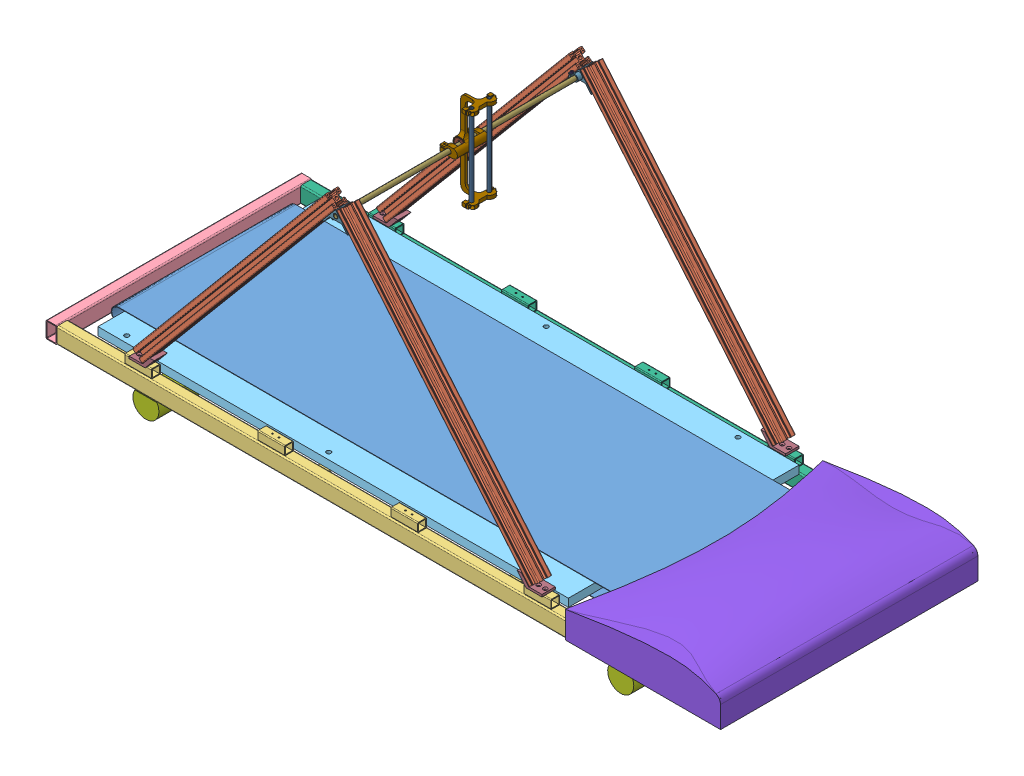
SolidWorks assembly treadmill, configuration Default. Lengths in mm.
37 component instances, 17 part files, 89 mates.
Components (placement in the parent):
- running_area-1: running_area [Default] at origin size (1202 32 400)
- Bosch Profile - 30x30-1: Bosch Profile - 30x30 [Predeterminado] at (-18.609 533.7218 -274.5) x (0 0 -1) z (-0.642788 -0.766044 0) size (30 30 675)
- Bosch Profile - 30x30-2: Bosch Profile - 30x30 [Predeterminado] at (6.609 533.7218 -274.5) x (0 0 1) z (0.642788 -0.766044 0) size (30 30 675)
- Bosch Profile - 30x30-3: Bosch Profile - 30x30 [Predeterminado] at (-18.609 533.7218 274.5) x (0 0 -1) z (-0.642788 -0.766044 0) size (30 30 675)
- Bosch Profile - 30x30-4: Bosch Profile - 30x30 [Predeterminado] at (6.609 533.7218 274.5) x (0 0 1) z (0.642788 -0.766044 0) size (30 30 675)
- Structure - right side-1: Structure - right side [Default] at (-636 -55 274.5) x (0 0 -1) z (1 0 0) size (54 57 1470)
- Structure - front-1: Structure - front [Default] at (-648.5 -55 0) size (25 37 574)
- Structure - front-2: Structure - front [Default] at (846.5 -55 0) size (25 37 574)
- Structure - table-1: Structure - table [Default] at (-571 -18 0) x (0 0 -1) z (1 0 0) size (520 18 1060)
- MirrorStructure - right side-3: MirrorStructure - right side [Default] at (-636 -55 -274.5) x (0 0 1) z (-1 0 0) size (54 57 1470)
- Structure - legs-1: Structure - legs [Default] at (-436 -55 0) size (58.89 45 574)
- Structure - legs-3: Structure - legs [Default] at (634 -55 0) size (58.89 45 574)
- Cover-1: Cover [Default] at (862 -55 0) x (0 0 -1) z (1 0 0) size (598.07 112.89 350.23)
- Interface - Robot holder-1: Interface - Robot holder [Default] at (25.0619 512.5003 0) x (0 0 -1) z (1 0 0) size (70 190 68.16)
- Interface - Jumping rods-1: Interface - Jumping rods [Default] at (30.7648 512.5003 -20) x (0 1 0) z (0 0 1) size (190 8 8)
- Interface - Jumping rods-2: Interface - Jumping rods [Default] at (30.7648 512.5003 20) x (0 1 0) z (-0.99626 0 0.086407) size (190 8 8)
- bearing_S 6000-2RS_618-9991-1: bearing_S 6000-2RS_618-9991 [Predeterminado] at (-6 512.5003 -9.8) size (26 26 8)
- bearing_S 6000-2RS_618-9991-2: bearing_S 6000-2RS_618-9991 [Predeterminado] at (-6 512.5003 1.8) size (26 26 8)
- Interface - Structure rod-1: Interface - Structure rod [Default] at (-6 512.5003 0) x (0 1 0) z (-1 0 0) size (10 579 10)
- Printed Parts - Profile - Treadmill-1: Printed Parts - Profile - Treadmill [Default] at (429 7 -274.5) x (0 0 -1) z (1 0 0) size (30 24.15 56.07)
- Printed Parts - Profile - Treadmill-2: Printed Parts - Profile - Treadmill [Default] at (-441 7 -274.5) x (0 0 1) z (-1 0 0) size (30 24.15 56.07)
- Printed Parts - Profile - Treadmill-3: Printed Parts - Profile - Treadmill [Default] at (-441 7 274.5) x (0 0 1) z (-1 0 0) size (30 24.15 56.07)
- Printed Parts - Profile - Treadmill-4: Printed Parts - Profile - Treadmill [Default] at (429 7 274.5) x (0 0 -1) z (1 0 0) size (30 24.15 56.07)
- Printed Parts - Profile - Robot-1: Printed Parts - Profile - Robot [Default] at (-6 512.5003 -274.5) x (0 0 -1) z (1 0 0) size (40 36.53 58.07)
- Printed Parts - Profile - Robot-2: Printed Parts - Profile - Robot [Default] at (-6 512.5003 274.5) x (0 0 1) z (-1 0 0) size (40 36.53 58.07)
- DIN 912 M6 x 10 --- 10N-6: DIN 912 M6 x 10 --- 10N [DIN 912 M6 x 10 --- 10N] at (413.3693 14.3327 -274.5) x (0.766044 0.642788 0) z (-0.079258 0.094456 0.992369) size (16 10 10)
- DIN 912 M6 x 10 --- 10N-10: DIN 912 M6 x 10 --- 10N [DIN 912 M6 x 10 --- 10N] at (-425.3693 14.3327 -274.5) x (-0.766044 0.642788 0) z (0.478639 0.570419 -0.667478) size (16 10 10)
- DIN 912 M6 x 10 --- 10N-11: DIN 912 M6 x 10 --- 10N [DIN 912 M6 x 10 --- 10N] at (413.3693 14.3327 274.5) x (0.766044 0.642788 0) z (0.079258 -0.094456 -0.992369) size (16 10 10)
- DIN 912 M6 x 10 --- 10N-12: DIN 912 M6 x 10 --- 10N [DIN 912 M6 x 10 --- 10N] at (-425.3693 14.3327 274.5) x (-0.766044 0.642788 0) z (0.478639 0.570419 -0.667478) size (16 10 10)
- DIN 912 M6 x 10 --- 10N-13: DIN 912 M6 x 10 --- 10N [DIN 912 M6 x 10 --- 10N] at (9.7148 492.6831 -274.5) x (0.766044 0.642788 0) z (0.596176 -0.710494 -0.373861) size (16 10 10)
- DIN 912 M6 x 10 --- 10N-14: DIN 912 M6 x 10 --- 10N [DIN 912 M6 x 10 --- 10N] at (-21.7148 492.6831 -274.5) x (-0.766044 0.642788 0) z (0.474764 0.565802 -0.674141) size (16 10 10)
- DIN 912 M6 x 10 --- 10N-15: DIN 912 M6 x 10 --- 10N [DIN 912 M6 x 10 --- 10N] at (-21.7148 492.6831 274.5) x (-0.766044 0.642788 0) z (0.474764 0.565802 -0.674141) size (16 10 10)
- DIN 912 M6 x 10 --- 10N-16: DIN 912 M6 x 10 --- 10N [DIN 912 M6 x 10 --- 10N] at (9.7148 492.6831 274.5) x (0.766044 0.642788 0) z (0.596176 -0.710494 -0.373861) size (16 10 10)
- klee M3x5-1: klee M3x5 [Default] at (4.5366 505.2503 253.5) x (1 0 0) z (0 -1 0) size (4.8 4.8 6.21)
- klee M3x5-2: klee M3x5 [Default] at (-16.5366 505.2503 -253.5) x (1 0 0) z (0 -1 0) size (4.8 4.8 6.21)
- DIN 912 M3 x 6 --- 6N-1: DIN 912 M3 x 6 --- 6N [DIN 912 M3 x 6 --- 6N] at (-16.5366 518.7503 -253.5) x (0 -1 0) z (0.377809 0 0.925884) size (9 5.5 5.5)
- DIN 912 M3 x 6 --- 6N-2: DIN 912 M3 x 6 --- 6N [DIN 912 M3 x 6 --- 6N] at (4.5366 518.7503 253.5) x (0 -1 0) z (0.377809 0 0.925884) size (9 5.5 5.5)
Mates (geometry in assembly coordinates):
- Coincident1: coincident: plane of running_area-1 through (0 0 0) normal (0 0 1); plane of assembly through (0 0 0) normal (0 0 1)
- Coincident2: coincident: plane of running_area-1 through (0 0 0) normal (0 1 0); plane of assembly through (0 0 0) normal (0 1 0)
- Coincident3: coincident aligned: plane of running_area-1 through (0 0 0) normal (1 0 0); plane of assembly through (0 0 0) normal (1 0 0)
- Coincident11: coincident aligned: plane of Bosch Profile - 30x30-1 through (-456.5507 20.0486 -259.5) normal (0 0 1); plane of Bosch Profile - 30x30-2 through (444.5507 20.0486 -259.5) normal (0 0 1)
- Coincident16: coincident aligned: plane of Bosch Profile - 30x30-3 through (-456.5507 20.0486 289.5) normal (0 0 1); plane of Bosch Profile - 30x30-4 through (444.5507 20.0486 289.5) normal (0 0 1)
- Width1: width anti-aligned: plane of Structure - table-1 through (-571 0 -260) normal (0 0 -1); plane of Structure - table-1 through (-571 0 260) normal (0 0 1); plane of running_area-1 through (-585 -15 200) normal (0 0 1); plane of running_area-1 through (-585 -15 -200) normal (0 0 -1)
- Concentric1: concentric anti-aligned: cylinder of Structure - right side-1 through (-521 -25 245) axis (0 -1 0) radius 4; cylinder of Structure - table-1 through (-521 -18 245) axis (0 1 0) radius 5
- Parallel1: parallel anti-aligned: plane of Structure - right side-1 through (834 -21 262) normal (0 0 -1); plane of Structure - table-1 through (-571 0 260) normal (0 0 1)
- Coincident18: coincident anti-aligned: plane of Structure - right side-1 through (834 -21 284) normal (1 0 0); plane of Structure - front-2 through (834 -21 287) normal (-1 0 0)
- Coincident19: coincident aligned: plane of Structure - right side-1 through (834 -21 287) normal (0 0 1); plane of Structure - front-2 through (837 -21 287) normal (0 0 1)
- Coincident20: coincident aligned: plane of Structure - right side-1 through (834 -21 287) normal (0 0 1); plane of Structure - front-1 through (-658 -21 287) normal (0 0 1)
- Coincident21: coincident aligned: plane of Structure - right side-1 through (834 -18 284) normal (0 1 0); plane of Structure - front-1 through (-658 -18 287) normal (0 1 0)
- Coincident22: coincident anti-aligned: plane of Structure - right side-1 through (-636 -21 284) normal (-1 0 0); plane of Structure - front-1 through (-636 -21 287) normal (1 0 0)
- Coincident23: coincident aligned: plane of Structure - right side-1 through (834 -18 284) normal (0 1 0); plane of Structure - front-2 through (837 -18 287) normal (0 1 0)
- Coincident25: coincident anti-aligned: plane of running_area-1 through (-585 0 200) normal (0 -1 0); plane of Structure - table-1 through (-571 0 0) normal (0 1 0)
- Distance1: distance = 35 mm anti-aligned: cylinder of running_area-1 through (-585 -15 200) axis (0 0 -1) radius 16; plane of Structure - front-1 through (-636 -21 287) normal (1 0 0)
- Coincident27: coincident aligned: plane of MirrorStructure - right side-3 through (834 -21 -287) normal (0 0 -1); plane of Structure - legs-1 through (-436 -70.5556 -287) normal (0 0 -1)
- Coincident29: coincident aligned: plane of Structure - legs-1 through (-436 -70.5556 -287) normal (0 0 -1); plane of Structure - legs-3 through (634 -70.5556 -287) normal (0 0 -1)
- Coincident33: coincident anti-aligned: plane of MirrorStructure - right side-3 through (834 -55 -284) normal (0 -1 0); plane of Structure - legs-1 through (-461 -55 287) normal (0 1 0)
- Coincident34: coincident anti-aligned: plane of Structure - right side-1 through (834 -18 284) normal (0 1 0); plane of Structure - table-1 through (-571 -18 0) normal (0 -1 0)
- Distance2: distance = 200 mm: point of Structure - legs-1; plane of Structure - front-1 through (-661 -21 287) normal (-1 0 0)
- Distance3: distance = 200 mm: point of Structure - legs-3; plane of Structure - front-2 through (859 -21 287) normal (1 0 0)
- Width2: width anti-aligned: plane of Cover-1 through (691.5068 28.631 287) normal (0 0 -1); plane of Cover-1 through (691.5068 28.631 -287) normal (0 0 1); plane of Structure - right side-1 through (834 -21 287) normal (0 0 1); plane of MirrorStructure - right side-3 through (834 -21 -287) normal (0 0 -1)
- Coincident39: coincident anti-aligned: plane of Structure - front-2 through (859 -21 287) normal (1 0 0); plane of Cover-1 through (859 -55 290) normal (-1 0 0)
- Coincident41: coincident aligned: plane of MirrorStructure - right side-3 through (834 -55 -284) normal (0 -1 0); plane of Cover-1 through (512 -55 290) normal (0 -1 0)
- Concentric2: concentric anti-aligned: cylinder of Interface - Jumping rods-1 through (47.6845 587.3362 -20) axis (0 -1 0) radius 4; cylinder of Interface - Robot holder-1 through (47.6845 579.3362 -20) axis (0 1 0) radius 4.35
- Coincident42: coincident aligned: plane of Interface - Robot holder-1 through (53.3874 587.3362 -2.5) normal (0 1 0); plane of Interface - Jumping rods-1 through (47.6845 587.3362 -20) normal (0 1 0)
- Concentric3: concentric anti-aligned: cylinder of Interface - Robot holder-1 through (47.6845 579.3362 20) axis (0 1 0) radius 4.35; cylinder of Interface - Jumping rods-2 through (47.6845 587.3362 20) axis (0 -1 0) radius 4
- Coincident43: coincident aligned: plane of Interface - Robot holder-1 through (53.3874 587.3362 -2.5) normal (0 1 0); plane of Interface - Jumping rods-2 through (47.6845 587.3362 20) normal (0 1 0)
- Width3: width anti-aligned: plane of Interface - Robot holder-1 through (41.9816 492.3362 -2.5) normal (0 0 -1); plane of Interface - Robot holder-1 through (41.9816 492.3362 2.5) normal (0 0 1); plane of Bosch Profile - 30x30-4 through (444.5507 20.0486 289.5) normal (0 0 1); plane of Bosch Profile - 30x30-2 through (444.5507 20.0486 -289.5) normal (0 0 -1)
- Concentric4: concentric aligned: cylinder of Interface - Robot holder-1 through (10.9197 492.3362 -1.8) axis (0 0 -1) radius 13.6; cylinder of bearing_S 6000-2RS_618-9991-1 through (10.9197 492.3362 -1.8) axis (0 0 -1) radius 5
- Coincident44: coincident anti-aligned: plane of Interface - Robot holder-1 through (10.9197 492.3362 -1.8) normal (0 0 -1); plane of bearing_S 6000-2RS_618-9991-1 through (10.9197 492.3362 -1.8) normal (0 0 1)
- Concentric6: concentric anti-aligned: cylinder of Interface - Robot holder-1 through (10.9197 492.3362 -10) axis (0 0 1) radius 15; cylinder of bearing_S 6000-2RS_618-9991-2 through (10.9197 492.3362 9.8) axis (0 0 -1) radius 13
- Coincident45: coincident anti-aligned: plane of Interface - Robot holder-1 through (10.9197 492.3362 1.8) normal (0 0 1); plane of bearing_S 6000-2RS_618-9991-2 through (10.9197 492.3362 1.8) normal (0 0 -1)
- Concentric7: concentric anti-aligned: cylinder of bearing_S 6000-2RS_618-9991-1 through (10.9197 492.3362 -1.8) axis (0 0 -1) radius 5; cylinder of Interface - Structure rod-1 through (10.9197 492.3362 -289.5) axis (0 0 1) radius 5
- Coincident46: coincident aligned: plane of Bosch Profile - 30x30-1 through (-448.4306 13.235 -289.5) normal (0 0 -1); circle of Interface - Structure rod-1
- Parallel3: parallel anti-aligned: plane of Interface - Robot holder-1 through (5.9197 587.3362 -2.5) normal (-1 0 0); plane of assembly through (0 0 0) normal (1 0 0)
- Concentric8: concentric aligned: cylinder of Interface - Structure rod-1 through (10.9197 492.3362 -289.5) axis (0 0 1) radius 5; cylinder of Printed Parts - Profile - Robot-1 through (10.9197 492.3362 -289.5) axis (0 0 1) radius 5.3
- Coincident61: coincident aligned: plane of Bosch Profile - 30x30-1 through (-456.5507 20.0486 -289.5) normal (0 0 -1); plane of Printed Parts - Profile - Robot-1 through (10.9197 492.3362 -289.5) normal (0 0 -1)
- Coincident62: coincident anti-aligned: plane of Bosch Profile - 30x30-4 through (429 7 279.8) normal (-0.766044 -0.642788 0); plane of Printed Parts - Profile - Robot-2 through (10.9197 505.2487 289.5) normal (0.766044 0.642788 0)
- Concentric9: concentric anti-aligned: cylinder of Interface - Structure rod-1 through (10.9197 492.3362 -289.5) axis (0 0 1) radius 5; cylinder of Printed Parts - Profile - Robot-2 through (10.9197 492.3362 289.5) axis (0 0 -1) radius 5.3
- Coincident63: coincident aligned: plane of Bosch Profile - 30x30-4 through (436.4306 13.235 289.5) normal (0 0 1); plane of Printed Parts - Profile - Robot-2 through (10.9197 492.3362 289.5) normal (0 0 1)
- Concentric101: concentric anti-aligned: cone of Printed Parts - Profile - Treadmill-1 through (413.0629 14.0756 -274.5) axis (0.766044 0.642788 0); cylinder of DIN 912 M6 x 10 --- 10N-6 through (389.0474 -6.0758 -274.5) axis (-0.766044 -0.642788 0) radius 5
- Coincident641: coincident anti-aligned: plane of Printed Parts - Profile - Treadmill-1 through (417.9656 18.1894 -280) normal (-0.766044 -0.642788 0); plane of DIN 912 M6 x 10 --- 10N-6 through (414.7762 21.9904 -275.1165) normal (0.766044 0.642788 0)
- Concentric14: concentric aligned: cylinder of Printed Parts - Profile - Treadmill-2 through (-425.0629 14.0756 -274.5) axis (0.766044 -0.642788 0) radius 5.5; cylinder of DIN 912 M6 x 10 --- 10N-10 through (-401.0474 -6.0758 -274.5) axis (0.766044 -0.642788 0) radius 5
- Coincident68: coincident anti-aligned: plane of Printed Parts - Profile - Treadmill-2 through (-429.9656 18.1894 -269) normal (0.766044 -0.642788 0); plane of DIN 912 M6 x 10 --- 10N-10 through (-427.8204 20.746 -270.7769) normal (-0.766044 0.642788 0)
- Concentric15: concentric aligned: cylinder of Printed Parts - Profile - Treadmill-4 through (413.0629 14.0756 274.5) axis (-0.766044 -0.642788 0) radius 5.5; cylinder of DIN 912 M6 x 10 --- 10N-11 through (389.0474 -6.0758 274.5) axis (-0.766044 -0.642788 0) radius 5
- Coincident69: coincident anti-aligned: plane of Printed Parts - Profile - Treadmill-4 through (417.9656 18.1894 269) normal (-0.766044 -0.642788 0); plane of DIN 912 M6 x 10 --- 10N-11 through (421.155 14.3884 275.1165) normal (0.766044 0.642788 0)
- Concentric16: concentric aligned: cylinder of Printed Parts - Profile - Treadmill-3 through (-425.0629 14.0756 274.5) axis (0.766044 -0.642788 0) radius 5.5; cylinder of DIN 912 M6 x 10 --- 10N-12 through (-401.0474 -6.0758 274.5) axis (0.766044 -0.642788 0) radius 5
- Coincident70: coincident anti-aligned: plane of Printed Parts - Profile - Treadmill-3 through (-429.9656 18.1894 280) normal (0.766044 -0.642788 0); plane of DIN 912 M6 x 10 --- 10N-12 through (-427.8204 20.746 278.2231) normal (-0.766044 0.642788 0)
- Coincident71: coincident aligned: plane of Bosch Profile - 30x30-3 through (-456.5507 20.0486 289.5) normal (0 0 1); plane of Printed Parts - Profile - Treadmill-3 through (-471 2 289.5) normal (0 0 1)
- Concentric17: concentric aligned: cylinder of Printed Parts - Profile - Robot-1 through (31.2307 476.3758 -274.5) axis (-0.766044 -0.642788 0) radius 3.3; cylinder of DIN 912 M6 x 10 --- 10N-13 through (2.3125 452.1106 -274.5) axis (-0.766044 -0.642788 0) radius 5
- Coincident72: coincident anti-aligned: plane of Printed Parts - Profile - Robot-1 through (37.6586 468.7154 -289.5) normal (-0.766044 -0.642788 0); plane of DIN 912 M6 x 10 --- 10N-13 through (32.4323 474.9438 -269.8626) normal (0.766044 0.642788 0)
- Concentric18: concentric aligned: cylinder of Printed Parts - Profile - Robot-1 through (-9.3914 476.3758 -274.5) axis (0.766044 -0.642788 0) radius 3.3; cylinder of DIN 912 M6 x 10 --- 10N-14 through (19.5268 452.1106 -274.5) axis (0.766044 -0.642788 0) radius 5
- Coincident73: coincident anti-aligned: plane of Printed Parts - Profile - Robot-1 through (-15.8193 468.7154 -289.5) normal (0.766044 -0.642788 0); plane of DIN 912 M6 x 10 --- 10N-14 through (-7.2248 478.9579 -270.807) normal (-0.766044 0.642788 0)
- Concentric19: concentric aligned: cylinder of Printed Parts - Profile - Robot-2 through (-9.3914 476.3758 274.5) axis (0.766044 -0.642788 0) radius 3.3; cylinder of DIN 912 M6 x 10 --- 10N-15 through (19.5268 452.1106 274.5) axis (0.766044 -0.642788 0) radius 5
- Coincident74: coincident anti-aligned: plane of Printed Parts - Profile - Robot-2 through (-15.8193 468.7154 289.5) normal (0.766044 -0.642788 0); plane of DIN 912 M6 x 10 --- 10N-15 through (-7.2248 478.9579 278.193) normal (-0.766044 0.642788 0)
- Concentric20: concentric aligned: cylinder of Printed Parts - Profile - Robot-2 through (31.2307 476.3758 274.5) axis (-0.766044 -0.642788 0) radius 3.3; cylinder of DIN 912 M6 x 10 --- 10N-16 through (2.3125 452.1106 274.5) axis (-0.766044 -0.642788 0) radius 5
- Coincident75: coincident anti-aligned: plane of Printed Parts - Profile - Robot-2 through (37.6586 468.7154 289.5) normal (-0.766044 -0.642788 0); plane of DIN 912 M6 x 10 --- 10N-16 through (32.4323 474.9438 279.1374) normal (0.766044 0.642788 0)
- Concentric21: concentric anti-aligned: cylinder of Printed Parts - Profile - Robot-2 through (21.4563 468.7154 253.5) axis (0 1 0) radius 2.35; cylinder of klee M3x5-1 through (21.4563 485.0862 253.5) axis (0 -1 0) radius 1.5
- Coincident76: coincident aligned: plane of Printed Parts - Profile - Robot-2 through (16.0701 491.0862 257.5) normal (0 1 0); plane of klee M3x5-1 through (21.4563 491.0862 253.5) normal (0 1 0)
- Concentric22: concentric anti-aligned: cylinder of Printed Parts - Profile - Robot-1 through (0.383 468.7154 -253.5) axis (0 1 0) radius 2.35; cylinder of klee M3x5-2 through (0.383 485.0862 -253.5) axis (0 -1 0) radius 1.5
- Coincident77: coincident aligned: plane of Printed Parts - Profile - Robot-1 through (5.7692 491.0862 -257.5) normal (0 1 0); plane of klee M3x5-2 through (0.383 491.0862 -253.5) normal (0 1 0)
- Concentric23: concentric aligned: cylinder of Printed Parts - Profile - Robot-1 through (0.383 468.7154 -253.5) axis (0 1 0) radius 2.35; cylinder of DIN 912 M3 x 6 --- 6N-1 through (0.383 530.3362 -253.5) axis (0 1 0) radius 2.75
- Coincident78: coincident anti-aligned: plane of Printed Parts - Profile - Robot-1 through (-3.617 495.5862 -249.5) normal (0 1 0); plane of DIN 912 M3 x 6 --- 6N-1 through (2.9292 495.5862 -254.539) normal (0 -1 0)
- Concentric24: concentric aligned: cylinder of Printed Parts - Profile - Robot-2 through (21.4563 468.7154 253.5) axis (0 1 0) radius 2.35; cylinder of DIN 912 M3 x 6 --- 6N-2 through (21.4563 530.3362 253.5) axis (0 1 0) radius 2.75
- Coincident79: coincident anti-aligned: plane of Printed Parts - Profile - Robot-2 through (25.4563 495.5862 249.5) normal (0 1 0); plane of DIN 912 M3 x 6 --- 6N-2 through (24.0025 495.5862 252.461) normal (0 -1 0)
- Parallel7: parallel aligned: plane of Interface - Jumping rods-1 through (47.6845 492.3362 -20) normal (0 0 1); plane of assembly through (0 0 0) normal (0 0 1)
- Parallel8: parallel anti-aligned: plane of Interface - Structure rod-1 through (10.9197 492.3362 0) normal (-1 0 0); plane of assembly through (0 0 0) normal (1 0 0)
- Concentric102: concentric aligned: cylinder of MirrorStructure - right side-3 through (-463.45 2 -274.5) axis (0 1 0) radius 1.6; cylinder of Printed Parts - Profile - Treadmill-2 through (-463.45 7 -274.5) axis (0 1 0) radius 2.25
- Concentric103: concentric aligned: cylinder of MirrorStructure - right side-3 through (-448.55 2 -274.5) axis (0 1 0) radius 1.6; cylinder of Printed Parts - Profile - Treadmill-2 through (-448.55 7 -274.5) axis (0 1 0) radius 2.25
- Coincident642: coincident anti-aligned: line of Bosch Profile - 30x30-1 through (-441 7 -287.3) axis (0 0 1); line of Printed Parts - Profile - Treadmill-2 through (-441 7 -259.5) axis (0 0 -1)
- Width4: width aligned: plane of Bosch Profile - 30x30-1 through (-448.4306 13.235 -289.5) normal (0 0 -1); plane of Bosch Profile - 30x30-1 through (-448.4306 13.235 -259.5) normal (0 0 1); plane of MirrorStructure - right side-3 through (834 -21 -287) normal (0 0 -1); plane of MirrorStructure - right side-3 through (834 -21 -262) normal (0 0 1)
- Coincident643: coincident anti-aligned: line of Bosch Profile - 30x30-2 through (429 7 -261.7) axis (0 0 -1); line of Printed Parts - Profile - Treadmill-1 through (429 7 -289.5) axis (0 0 1)
- Concentric104: concentric aligned: cylinder of MirrorStructure - right side-3 through (451.45 2 -274.5) axis (0 1 0) radius 1.6; cylinder of Printed Parts - Profile - Treadmill-1 through (451.45 7 -274.5) axis (0 1 0) radius 2.25
- Coincident644: coincident anti-aligned: plane of MirrorStructure - right side-3 through (474 2 -266.5) normal (0 1 0); plane of Printed Parts - Profile - Treadmill-1 through (459 2 -259.5) normal (0 -1 0)
- Coincident645: coincident anti-aligned: plane of MirrorStructure - right side-3 through (-426 2 -266.5) normal (0 1 0); plane of Printed Parts - Profile - Treadmill-2 through (-471 2 -289.5) normal (0 -1 0)
- Coincident646: coincident anti-aligned: plane of Bosch Profile - 30x30-1 through (-441 7 -279.8) normal (0.766044 -0.642788 0); plane of Printed Parts - Profile - Treadmill-2 through (-441 7 -325.0374) normal (-0.766044 0.642788 0)
- Coincident647: coincident anti-aligned: plane of Bosch Profile - 30x30-2 through (429 7 -269.2) normal (-0.766044 -0.642788 0); plane of Printed Parts - Profile - Treadmill-1 through (429 7 -223.9626) normal (0.766044 0.642788 0)
- Concentric105: concentric aligned: cylinder of Structure - right side-1 through (-448.55 2 274.5) axis (0 1 0) radius 1.6; cylinder of Printed Parts - Profile - Treadmill-3 through (-448.55 7 274.5) axis (0 1 0) radius 2.25
- Coincident651: coincident anti-aligned: plane of Structure - right side-1 through (-426 2 266.5) normal (0 1 0); plane of Printed Parts - Profile - Treadmill-3 through (-471 2 259.5) normal (0 -1 0)
- Concentric106: concentric aligned: cylinder of Structure - right side-1 through (436.55 2 274.5) axis (0 1 0) radius 1.6; cylinder of Printed Parts - Profile - Treadmill-4 through (436.55 7 274.5) axis (0 1 0) radius 2.25
- Coincident652: coincident anti-aligned: plane of Structure - right side-1 through (474 2 266.5) normal (0 1 0); plane of Printed Parts - Profile - Treadmill-4 through (459 2 289.5) normal (0 -1 0)
- Coincident653: coincident anti-aligned: plane of Bosch Profile - 30x30-4 through (429 7 279.8) normal (-0.766044 -0.642788 0); plane of Printed Parts - Profile - Treadmill-4 through (429 7 325.0374) normal (0.766044 0.642788 0)
- Coincident654: coincident anti-aligned: line of Bosch Profile - 30x30-4 through (429 7 287.3) axis (0 0 -1); line of Printed Parts - Profile - Treadmill-4 through (429 7 259.5) axis (0 0 1)
- Coincident655: coincident anti-aligned: plane of Bosch Profile - 30x30-3 through (-441 7 279.8) normal (0.766044 -0.642788 0); plane of Printed Parts - Profile - Treadmill-3 through (-441 7 223.9626) normal (-0.766044 0.642788 0)
- Coincident656: coincident anti-aligned: line of Bosch Profile - 30x30-3 through (-441 7 279.8) axis (0 0 1); line of Printed Parts - Profile - Treadmill-3 through (-441 7 289.5) axis (0 0 -1)
- Width5: width anti-aligned: plane of Bosch Profile - 30x30-3 through (-448.4306 13.235 289.5) normal (0 0 1); plane of Bosch Profile - 30x30-3 through (-448.4306 13.235 259.5) normal (0 0 -1); plane of Printed Parts - Profile - Treadmill-3 through (-471 2 259.5) normal (0 0 -1); plane of Printed Parts - Profile - Treadmill-3 through (-471 2 289.5) normal (0 0 1)
- Coincident657: coincident anti-aligned: plane of Bosch Profile - 30x30-1 through (-441 7 -279.8) normal (0.766044 -0.642788 0); plane of Printed Parts - Profile - Robot-1 through (-6 525.4128 -289.5) normal (-0.766044 0.642788 0)
